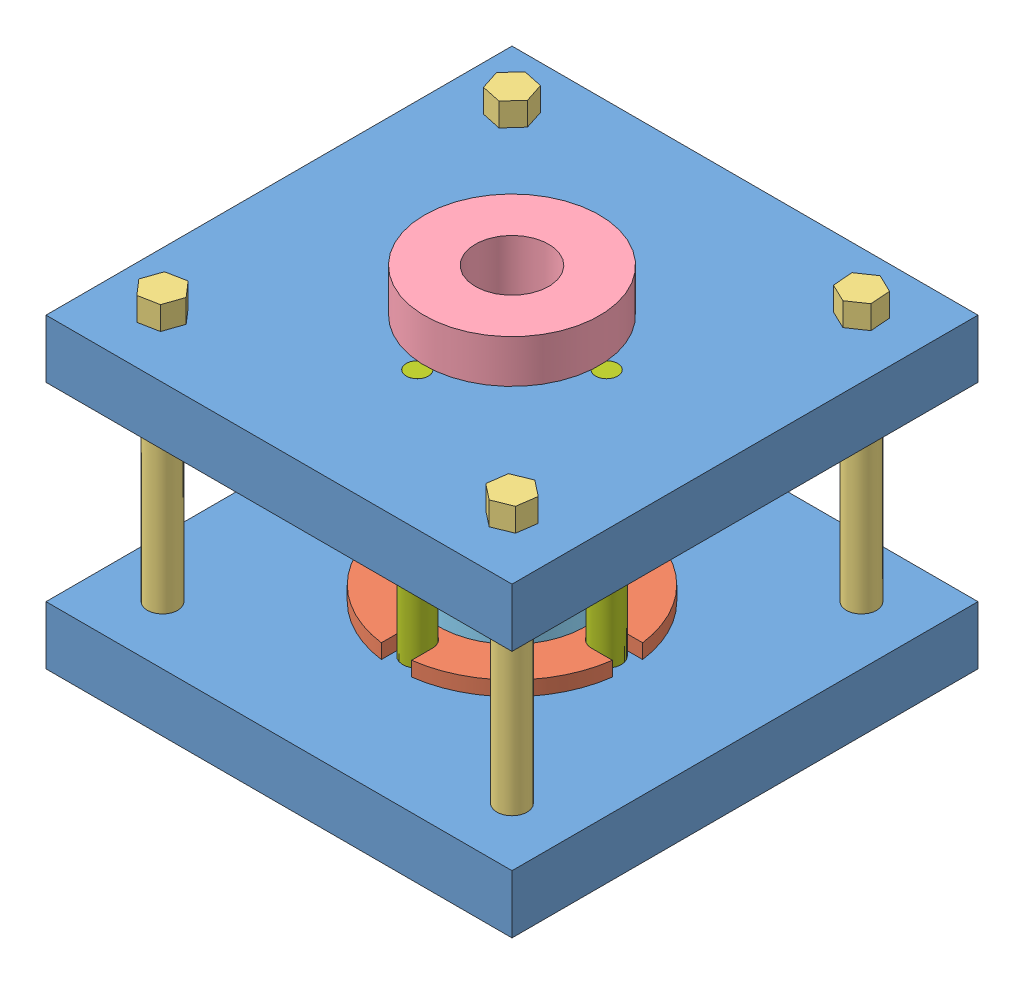
SolidWorks assembly Assem1, configuration Default. Lengths in mm.
Overall size (4 3.37 4).
17 component instances, 7 part files, 32 mates.
Components (placement in the parent):
- fixture assembly part1-1: fixture assembly part1 [Default] at (1.9109 2.0476 2.8769) size (4 0.5 4)
- fixture assembly Part2-1: fixture assembly Part2 [Default] at (1.9109 2.3601 2.8769) size (1.98 0.12 1.98)
- fixture assembly Part4-1: fixture assembly Part4 [Default] at (0.4109 4.5276 4.3769) x (-0.191145 0 -0.981562) z (0 -1 0) size (0.3 0.35 3.2)
- fixture assembly Part5-1: fixture assembly Part5 [Default] at (1.9109 3.8695 2.8769) size (1.5 3 1.5)
- fixture assembly Part6-1: fixture assembly Part6 [Default] at (1.9109 2.4226 2.8769) size (1.25 1.38 1.25)
- fixture assembly Part7-1: fixture assembly Part7 [Default] at (0.4109 1.5976 4.3769) size (0.4 0.2 0.35)
- fixture assembly Part3-11: fixture assembly Part3 [Default] at (2.7234 3.1126 2.8769) x (0 1 0) z (0 0 1) size (2.63 0.25 0.25)
- fixture assembly Part3-12: fixture assembly Part3 [Default] at (1.9109 3.1126 2.0644) x (0 1 0) z (0.188455 0 0.982082) size (2.63 0.25 0.25)
- fixture assembly Part3-14: fixture assembly Part3 [Default] at (1.0984 3.1126 2.8769) x (0 1 0) z (0.395734 0 0.918365) size (2.63 0.25 0.25)
- fixture assembly Part3-16: fixture assembly Part3 [Default] at (1.9109 3.1126 3.6894) x (0 1 0) z (0.188455 0 0.982082) size (2.63 0.25 0.25)
- fixture assembly part1-2: fixture assembly part1 [Default] at (1.9109 4.1776 2.8769) size (4 0.5 4)
- fixture assembly Part4-2: fixture assembly Part4 [Default] at (3.4109 4.5276 4.3769) x (-0.3727 0 -0.927952) z (0 -1 0) size (0.3 0.35 3.2)
- fixture assembly Part7-2: fixture assembly Part7 [Default] at (3.4109 1.5976 4.3769) x (0.998009 0 -0.063068) z (0.063068 0 0.998009) size (0.4 0.2 0.35)
- fixture assembly Part4-4: fixture assembly Part4 [Default] at (3.4109 4.5276 1.3769) x (-0.563979 0 -0.825789) z (0 -1 0) size (0.3 0.35 3.2)
- fixture assembly Part7-4: fixture assembly Part7 [Default] at (3.4109 1.5976 1.3769) x (0.976665 0 -0.214767) z (0.214767 0 0.976665) size (0.4 0.2 0.35)
- fixture assembly Part4-8: fixture assembly Part4 [Default] at (0.4109 4.5276 1.3769) x (-0.741853 0 -0.670562) z (0 -1 0) size (0.3 0.35 3.2)
- fixture assembly Part7-8: fixture assembly Part7 [Default] at (0.4109 1.5976 1.3769) x (0.5 0 0.866025) z (-0.866025 0 0.5) size (0.4 0.2 0.35)
Mates (geometry in assembly coordinates):
- Coincident1: coincident aligned: cylinder of fixture assembly part1-1 through (1.9109 2.2976 2.8769) axis (0 1 0) radius 0.5; circle of fixture assembly Part2-1
- Coincident2: coincident anti-aligned: plane of fixture assembly part1-1 through (1.9109 2.2976 2.8769) normal (0 1 0); plane of fixture assembly Part2-1 through (1.9109 2.2976 2.8769) normal (0 -1 0)
- Concentric1: concentric anti-aligned: cylinder of fixture assembly part1-1 through (2.7234 1.7976 2.8769) axis (0 1 0) radius 0.095; cylinder of fixture assembly Part3-11 through (2.7234 1.7976 2.8769) axis (0 -1 0) radius 0.095
- Coincident5: coincident anti-aligned: plane of fixture assembly part1-1 through (1.9109 2.2976 2.8769) normal (0 1 0); plane of fixture assembly Part3-11 through (2.7234 2.2976 2.8769) normal (0 -1 0)
- Concentric2: concentric anti-aligned: cylinder of fixture assembly part1-1 through (1.9109 1.7976 2.0644) axis (0 1 0) radius 0.095; cylinder of fixture assembly Part3-12 through (1.9109 1.7976 2.0644) axis (0 -1 0) radius 0.095
- Coincident6: coincident anti-aligned: plane of fixture assembly part1-1 through (1.9109 2.2976 2.8769) normal (0 1 0); plane of fixture assembly Part3-12 through (1.9109 2.2976 2.0644) normal (0 -1 0)
- Concentric3: concentric anti-aligned: cylinder of fixture assembly part1-1 through (1.0984 1.7976 2.8769) axis (0 1 0) radius 0.095; cylinder of fixture assembly Part3-14 through (1.0984 1.7976 2.8769) axis (0 -1 0) radius 0.095
- Coincident7: coincident anti-aligned: plane of fixture assembly part1-1 through (1.9109 2.2976 2.8769) normal (0 1 0); plane of fixture assembly Part3-14 through (1.0984 2.2976 2.8769) normal (0 -1 0)
- Concentric4: concentric anti-aligned: cylinder of fixture assembly part1-1 through (1.9109 1.7976 3.6894) axis (0 1 0) radius 0.095; cylinder of fixture assembly Part3-16 through (1.9109 1.7976 3.6894) axis (0 -1 0) radius 0.095
- Coincident8: coincident anti-aligned: plane of fixture assembly part1-1 through (1.9109 2.2976 2.8769) normal (0 1 0); plane of fixture assembly Part3-16 through (1.9109 2.2976 3.6894) normal (0 -1 0)
- Concentric5: concentric anti-aligned: cylinder of fixture assembly Part3-16 through (1.9109 1.7976 3.6894) axis (0 -1 0) radius 0.095; cylinder of fixture assembly part1-2 through (1.9109 3.9276 3.6894) axis (0 1 0) radius 0.095
- Coincident11: coincident anti-aligned: plane of fixture assembly Part3-14 through (1.0984 3.9276 2.8769) normal (0 1 0); plane of fixture assembly part1-2 through (1.9109 3.9276 2.8769) normal (0 -1 0)
- Concentric6: concentric anti-aligned: cylinder of fixture assembly Part6-1 through (1.9109 3.7976 2.8769) axis (0 -1 0) radius 0.5; cylinder of fixture assembly part1-2 through (1.9109 4.4276 2.8769) axis (0 1 0) radius 0.5
- Coincident12: coincident anti-aligned: plane of fixture assembly Part2-1 through (1.9109 2.4226 2.8769) normal (0 1 0); plane of fixture assembly Part6-1 through (1.9109 2.4226 2.8769) normal (0 -1 0)
- Concentric7: concentric aligned: cylinder of fixture assembly Part5-1 through (1.9109 4.7976 2.8769) axis (0 1 0) radius 0.5; cylinder of fixture assembly part1-2 through (1.9109 4.4276 2.8769) axis (0 1 0) radius 0.5
- Coincident13: coincident aligned: plane of fixture assembly part1-1 through (1.9109 1.7976 2.8769) normal (0 -1 0); plane of fixture assembly Part5-1 through (1.9109 1.7976 2.8769) normal (0 -1 0)
- Concentric8: concentric anti-aligned: cylinder of fixture assembly Part4-1 through (0.4109 1.4276 4.3769) axis (0 1 0) radius 0.13; cylinder of fixture assembly Part7-1 through (0.4109 1.7976 4.3769) axis (0 -1 0) radius 0.125
- Concentric9: concentric aligned: cylinder of fixture assembly part1-1 through (0.4109 2.2976 4.3769) axis (0 1 0) radius 0.13; cylinder of fixture assembly Part4-1 through (0.4109 1.4276 4.3769) axis (0 1 0) radius 0.13
- Coincident14: coincident anti-aligned: plane of fixture assembly Part4-1 through (0.4109 4.4276 4.3769) normal (0 -1 0); plane of fixture assembly part1-2 through (1.9109 4.4276 2.8769) normal (0 1 0)
- Coincident15: coincident anti-aligned: plane of fixture assembly part1-1 through (1.9109 1.7976 2.8769) normal (0 -1 0); plane of fixture assembly Part7-1 through (0.4109 1.7976 4.3769) normal (0 1 0)
- Concentric10: concentric anti-aligned: cylinder of fixture assembly Part4-2 through (3.4109 1.4276 4.3769) axis (0 1 0) radius 0.13; cylinder of fixture assembly Part7-2 through (3.4109 1.7976 4.3769) axis (0 -1 0) radius 0.125
- Concentric11: concentric aligned: circle of fixture assembly part1-1; cylinder of fixture assembly Part4-2 through (3.4109 1.4276 4.3769) axis (0 1 0) radius 0.13
- Coincident16: coincident anti-aligned: plane of fixture assembly part1-2 through (1.9109 4.4276 2.8769) normal (0 1 0); plane of fixture assembly Part4-2 through (3.4109 4.4276 4.3769) normal (0 -1 0)
- Concentric13: concentric anti-aligned: cylinder of fixture assembly Part4-4 through (3.4109 1.4276 1.3769) axis (0 1 0) radius 0.13; cylinder of fixture assembly Part7-4 through (3.4109 1.7976 1.3769) axis (0 -1 0) radius 0.125
- Concentric14: concentric aligned: circle of fixture assembly part1-1; cylinder of fixture assembly Part4-4 through (3.4109 1.4276 1.3769) axis (0 1 0) radius 0.13
- Coincident17: coincident anti-aligned: plane of fixture assembly part1-2 through (1.9109 4.4276 2.8769) normal (0 1 0); plane of fixture assembly Part4-4 through (3.4109 4.4276 1.3769) normal (0 -1 0)
- Concentric19: concentric anti-aligned: cylinder of fixture assembly Part4-8 through (0.4109 1.4276 1.3769) axis (0 1 0) radius 0.13; cylinder of fixture assembly Part7-8 through (0.4109 2.1482 1.3769) axis (0 -1 0) radius 0.125
- Concentric20: concentric aligned: cylinder of fixture assembly part1-2 through (0.4109 4.4276 1.3769) axis (0 1 0) radius 0.13; cylinder of fixture assembly Part4-8 through (0.4109 1.4276 1.3769) axis (0 1 0) radius 0.13
- Coincident19: coincident anti-aligned: plane of fixture assembly part1-2 through (1.9109 4.4276 2.8769) normal (0 1 0); plane of fixture assembly Part4-8 through (0.4109 4.4276 1.3769) normal (0 -1 0)
- Coincident20: coincident anti-aligned: plane of fixture assembly part1-1 through (1.9109 1.7976 2.8769) normal (0 -1 0); plane of fixture assembly Part7-2 through (3.4109 1.7976 4.3769) normal (0 1 0)
- Coincident21: coincident anti-aligned: plane of fixture assembly part1-1 through (1.9109 1.7976 2.8769) normal (0 -1 0); plane of fixture assembly Part7-4 through (3.4109 1.7976 1.3769) normal (0 1 0)
- Coincident29: coincident anti-aligned: plane of fixture assembly part1-1 through (1.9109 1.7976 2.8769) normal (0 -1 0); plane of fixture assembly Part7-8 through (0.4109 1.7976 1.3769) normal (0 1 0)
